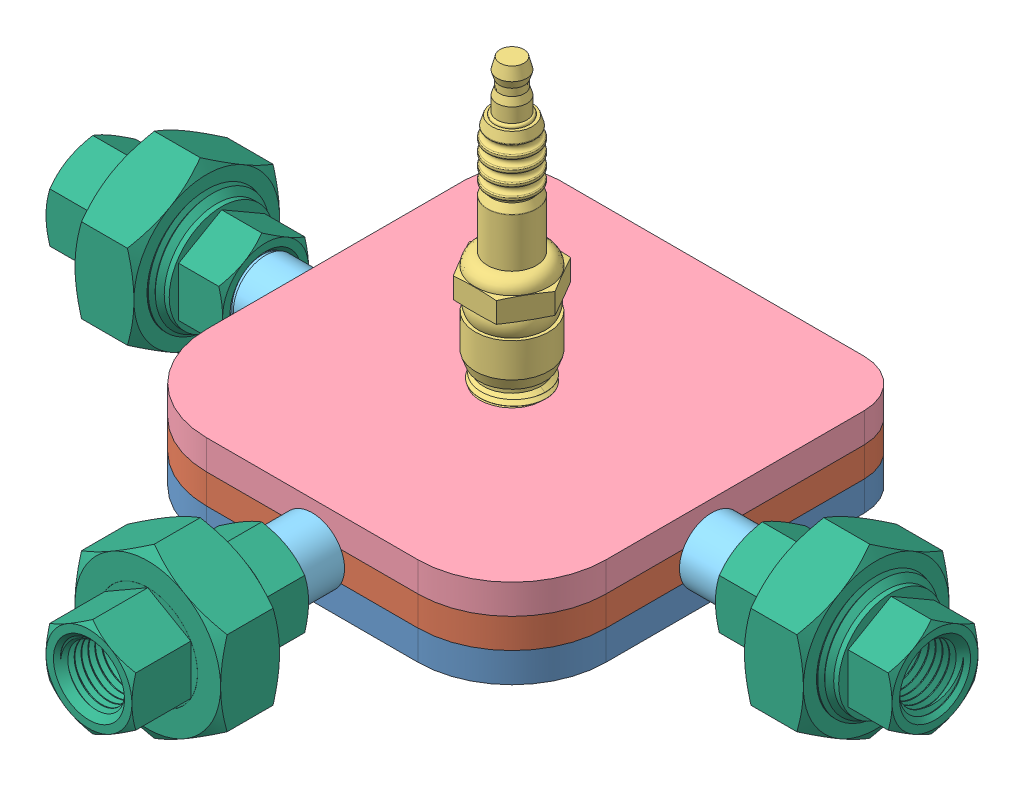
SolidWorks assembly detonation chamber, configuration Default. Lengths in mm.
Overall size (180.07 87.64 132.54).
10 component instances, 6 part files, 20 mates.
Components (placement in the parent):
- detonation bottom-1: detonation bottom [Default] at (-12.2158 42.7421 111.4281) size (85 6.3 85)
- detonation middle-1: detonation middle [Default] at (-12.2158 49.0421 111.4281) size (85 6.3 85)
- SW3dPS-1: SW3dPS [Default] at (30.2842 121.9409 68.9281) size (18.3 73.66 15.85)
- detonation top-1: detonation top [Default] at (-12.2158 55.3421 111.4281) size (85 6.3 85)
- 9157K110_STD-WALL 304-304L SS THRD ONE END PIPE NIPPLE-1: 9157K110_STD-WALL 304-304L SS THRD ONE END PIPE NIPPLE [9157K11] at (30.2842 52.1921 124.1281) x (0 0 1) z (-0.999746 -0.022559 0) size (25.47 14.55 14.44)
- 9157K110_STD-WALL 304-304L SS THRD ONE END PIPE NIPPLE-2: 9157K110_STD-WALL 304-304L SS THRD ONE END PIPE NIPPLE [9157K11] at (85.4842 52.1921 68.9281) size (25.47 14.55 14.44)
- 9157K110_STD-WALL 304-304L SS THRD ONE END PIPE NIPPLE-4: 9157K110_STD-WALL 304-304L SS THRD ONE END PIPE NIPPLE [9157K11] at (-24.9158 52.1921 68.9281) x (-1 0 0) z (0 -0.022559 -0.999746) size (25.47 14.55 14.44)
- 4464K484_TYPE 304 STAINLESS STL THREADED PIPE FITTING-1: 4464K484_TYPE 304 STAINLESS STL THREADED PIPE FITTING [4464K484] at (30.2842 52.1921 140.1684) size (30.99 35.78 37.59)
- 4464K484_TYPE 304 STAINLESS STL THREADED PIPE FITTING-2: 4464K484_TYPE 304 STAINLESS STL THREADED PIPE FITTING [4464K484] at (-40.9562 52.1921 68.9281) x (0 0 1) z (-1 0 0) size (30.99 35.78 37.59)
- 4464K484_TYPE 304 STAINLESS STL THREADED PIPE FITTING-4: 4464K484_TYPE 304 STAINLESS STL THREADED PIPE FITTING [4464K484] at (101.5246 52.1921 68.9281) x (0 0 1) z (-1 0 0) size (30.99 35.78 37.59)
Mates (geometry in assembly coordinates):
- Coincident1: coincident aligned: plane of detonation bottom-1 through (-12.2158 49.0421 111.4281) normal (0 0 1); plane of detonation middle-1 through (-12.2158 55.3421 111.4281) normal (0 0 1)
- Coincident2: coincident aligned: plane of detonation bottom-1 through (72.7842 49.0421 111.4281) normal (1 0 0); plane of detonation middle-1 through (72.7842 55.3421 111.4281) normal (1 0 0)
- Coincident3: coincident anti-aligned: plane of detonation bottom-1 through (-12.2158 49.0421 111.4281) normal (0 1 0); plane of detonation middle-1 through (-12.2158 49.0421 111.4281) normal (0 -1 0)
- Concentric1: concentric aligned: cylinder of SW3dPS-1 through (30.2842 85.9999 68.9281) axis (0 1 0) radius 7.8232; cylinder of detonation top-1 through (30.2842 55.3411 68.9281) axis (0 1 0) radius 6.4
- Coincident4: coincident aligned: plane of SW3dPS-1 through (30.2842 55.3421 68.9281) normal (0 -1 0); plane of detonation top-1 through (-12.2158 55.3421 111.4281) normal (0 -1 0)
- Coincident5: coincident anti-aligned: plane of detonation middle-1 through (-12.2158 55.3421 111.4281) normal (0 1 0); plane of detonation top-1 through (-12.2158 55.3421 111.4281) normal (0 -1 0)
- Coincident6: coincident aligned: plane of detonation middle-1 through (-12.2158 55.3421 111.4281) normal (0 0 1); plane of detonation top-1 through (-12.2158 61.6421 111.4281) normal (0 0 1)
- Coincident7: coincident aligned: plane of detonation middle-1 through (-12.2158 55.3421 111.4281) normal (-1 0 0); plane of detonation top-1 through (-12.2158 61.6421 111.4281) normal (-1 0 0)
- Coincident8: coincident anti-aligned: plane of detonation middle-1 through (-12.2158 55.3421 111.4281) normal (0 0 1); plane of 9157K110_STD-WALL 304-304L SS THRD ONE END PIPE NIPPLE-1 through (30.2842 52.1921 111.4281) normal (0 0 -1)
- Concentric4: concentric aligned: cylinder of detonation middle-1 through (30.2842 52.1921 26.4271) axis (0 0 1) radius 2.5; cylinder of 9157K110_STD-WALL 304-304L SS THRD ONE END PIPE NIPPLE-1 through (30.2842 52.1921 111.4281) axis (0 0 1) radius 4.6228
- Coincident10: coincident anti-aligned: plane of detonation middle-1 through (-12.2158 55.3421 111.4281) normal (-1 0 0); plane of 9157K110_STD-WALL 304-304L SS THRD ONE END PIPE NIPPLE-4 through (-12.2158 52.1921 68.9281) normal (1 0 0)
- Concentric5: concentric aligned: cylinder of detonation middle-1 through (72.7842 52.1921 68.9281) axis (-1 0 0) radius 2.5; cylinder of 9157K110_STD-WALL 304-304L SS THRD ONE END PIPE NIPPLE-4 through (-12.2158 52.1921 68.9281) axis (-1 0 0) radius 4.6228
- Coincident12: coincident anti-aligned: plane of detonation middle-1 through (72.7842 55.3421 111.4281) normal (1 0 0); plane of 9157K110_STD-WALL 304-304L SS THRD ONE END PIPE NIPPLE-2 through (72.7842 52.1921 68.9281) normal (-1 0 0)
- Concentric7: concentric anti-aligned: cylinder of detonation middle-1 through (72.7842 52.1921 68.9281) axis (-1 0 0) radius 2.5; cylinder of 9157K110_STD-WALL 304-304L SS THRD ONE END PIPE NIPPLE-2 through (72.7842 52.1921 68.9281) axis (1 0 0) radius 4.6228
- Concentric8: concentric aligned: cylinder of 9157K110_STD-WALL 304-304L SS THRD ONE END PIPE NIPPLE-1 through (30.2842 52.1921 111.4281) axis (0 0 1) radius 4.6228; circle of 4464K484_TYPE 304 STAINLESS STL THREADED PIPE FITTING-1
- Coincident13: coincident anti-aligned: circle of 9157K110_STD-WALL 304-304L SS THRD ONE END PIPE NIPPLE-1; plane of 4464K484_TYPE 304 STAINLESS STL THREADED PIPE FITTING-1 through (30.2842 52.1921 121.3724) normal (0 0 -1)
- Concentric9: concentric anti-aligned: cylinder of 9157K110_STD-WALL 304-304L SS THRD ONE END PIPE NIPPLE-4 through (-12.2158 52.1921 68.9281) axis (-1 0 0) radius 4.6228; circle of 4464K484_TYPE 304 STAINLESS STL THREADED PIPE FITTING-2
- Coincident14: coincident anti-aligned: circle of 9157K110_STD-WALL 304-304L SS THRD ONE END PIPE NIPPLE-4; plane of 4464K484_TYPE 304 STAINLESS STL THREADED PIPE FITTING-2 through (-22.1602 52.1921 68.9281) normal (1 0 0)
- Concentric11: concentric anti-aligned: cylinder of 9157K110_STD-WALL 304-304L SS THRD ONE END PIPE NIPPLE-2 through (72.7842 52.1921 68.9281) axis (1 0 0) radius 4.6228; circle of 4464K484_TYPE 304 STAINLESS STL THREADED PIPE FITTING-4
- Coincident16: coincident anti-aligned: circle of 9157K110_STD-WALL 304-304L SS THRD ONE END PIPE NIPPLE-2; plane of 4464K484_TYPE 304 STAINLESS STL THREADED PIPE FITTING-4 through (82.7286 52.1921 68.9281) normal (-1 0 0)
